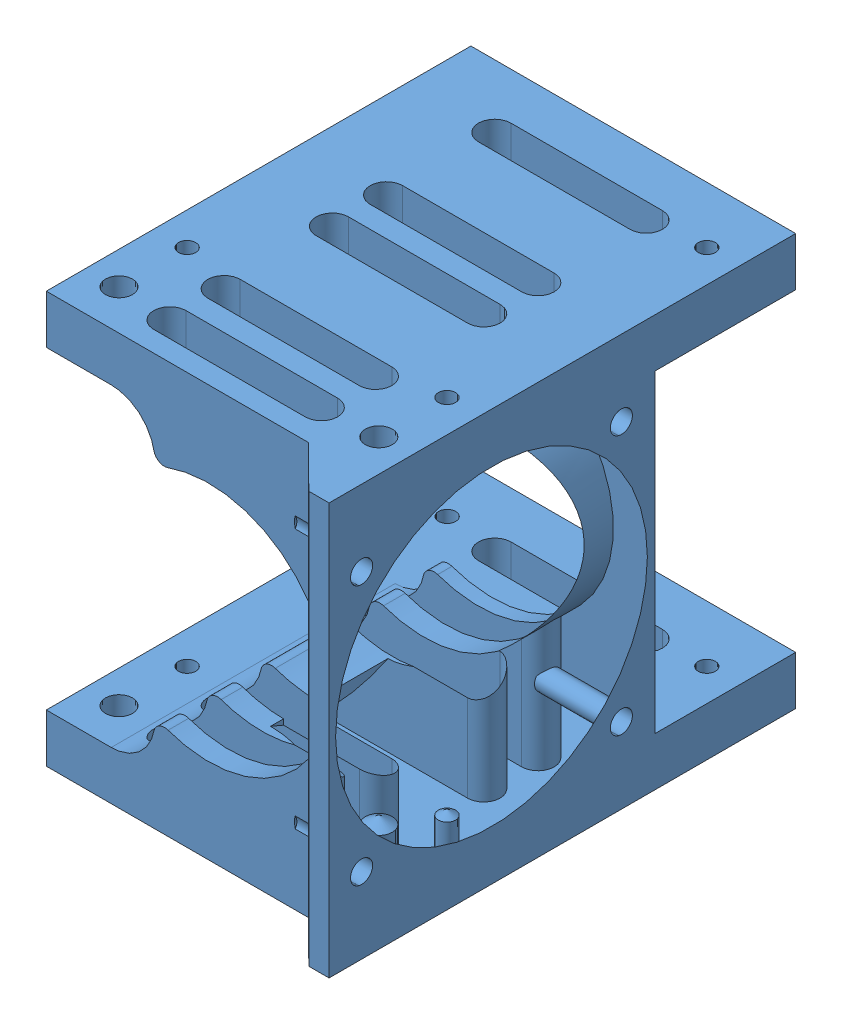
SolidWorks assembly E3Dv6_PRO_3010, configuration Default. Lengths in mm.
Overall size (30 38 43.1).
8 component instances, 5 part files, 0 mates.
Components (placement in the parent):
- E3Dv6_PRO_3010.stp-1: E3Dv6_PRO_3010.stp [Default] at origin size (40.99 58 61.3)
  - ________-3010.stp-1: ________-3010.stp [Default] at (1 2.7759 -25) x (0 0 -1) z (0 -1 0) size (30 30 10) (hidden)
  - ____-E3Dv6.stp-1: ____-E3Dv6.stp [Default] at (0 21.7259 -37.3574) x (0 1 0) z (0 0 1) size (22.3 26.65 61.3) (hidden)
  - ________-3010.stp-2: ________-3010.stp [Default] at (-1 40.6759 -25) x (0 0 -1) z (0 1 0) size (30 30 10) (hidden)
  - ______-3010.stp-1: ______-3010.stp [Default] at origin size (30 10 10) (hidden)
  - ______-3010.stp-2: ______-3010.stp [Default] at (0 43.4517 0) x (-1 0 0) z (0 0 1) size (30 10 10) (hidden)
  - ________-3010-0.stp-1: ________-3010-0.stp [Default] at (25.4859 21.7259 -10.1259) x (0 1 0) z (-1 0 0) size (30 30.54 10.5) (hidden)
  - E3Dv6_______3010.stp-1: E3Dv6_______3010.stp [Default] at origin size (30 38 43.1)
